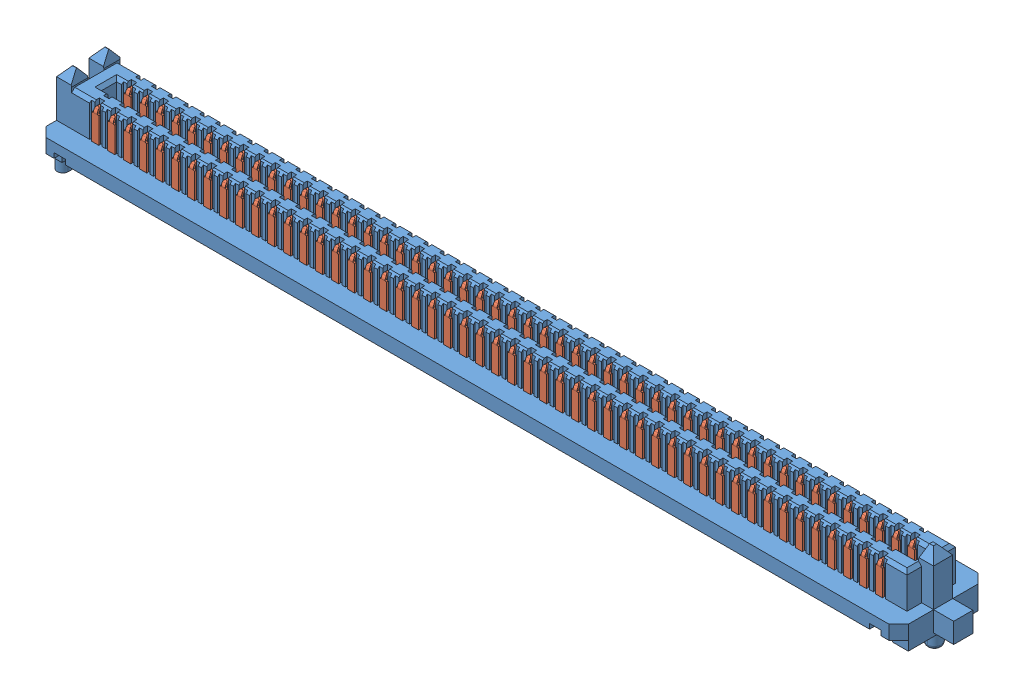
SolidWorks assembly Assem1, configuration Default. Lengths in mm.
Overall size (70.08 6.88 7.06).
5 component instances, 4 part files, 3 mates.
Components (placement in the parent):
- SEAM_50_02_0_L_04_2_A_K_TR-1: SEAM_50_02_0_L_04_2_A_K_TR [Default] at (0 1.8542 0) size (70.08 6.88 7.06)
  - _SEAM_50_02_0_L_04_1_A_K_TR_body_2-1: _SEAM_50_02_0_L_04_1_A_K_TR_body_2 [Default] at origin size (70.08 6.88 7.06)
  - _SEAM_50_02_0_L_04_1_A_K_TR_conn_4-1: _SEAM_50_02_0_L_04_1_A_K_TR_conn_4 [Default] at origin size (67.97 4.25 6.55)
  - _SEAM_K_Pad_04_6-1: _SEAM_K_Pad_04_6 [Default] at (0 2.7432 0) size (5.99 0.13 5.99) (hidden)
  - _SEAM_Triangle_8-1: _SEAM_Triangle_8 [Default] at (32.2834 1.3462 -1.6764) x (-1 0 0) z (0 0 -1) size (1.02 1.27 0.13)
Mates (geometry in assembly coordinates):
- Coincident1: coincident: plane of ? through (32.9692 0 2.7686) normal (0 -1 0)
- Coincident2: coincident: plane of ? through (0 1.8542 0) normal (0 0 1)
- Coincident3: coincident: plane of ? through (0 1.8542 0) normal (1 0 0)
